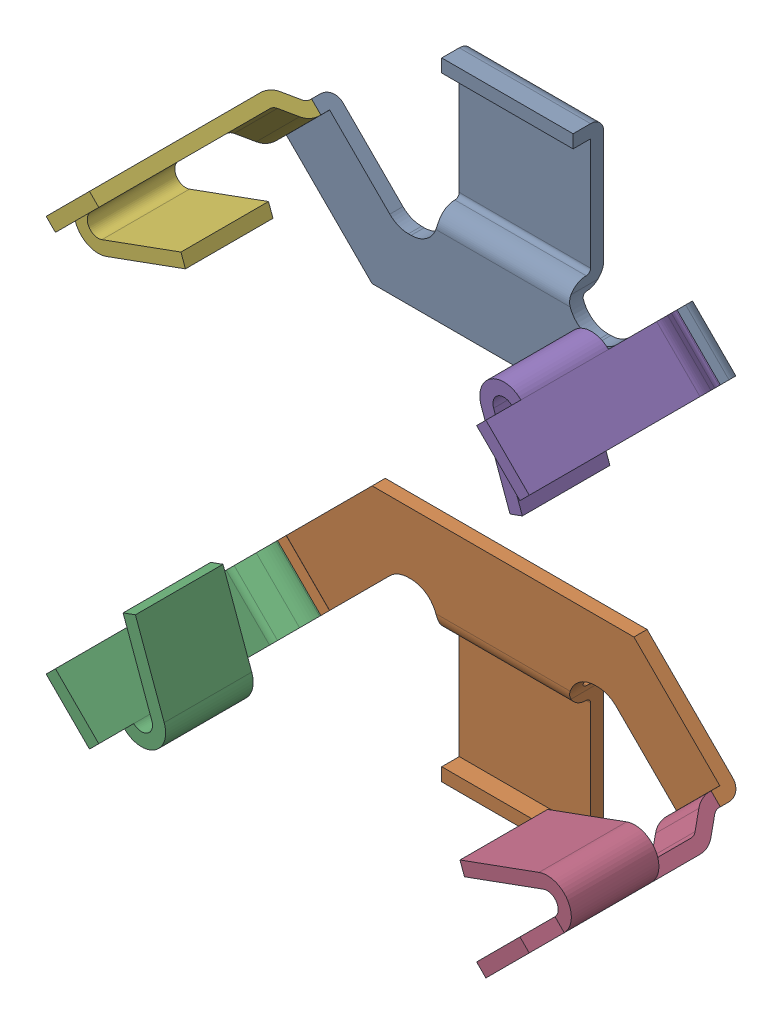
SolidWorks assembly Leadframe, configuration Default. Lengths in mm.
Overall size (7.19 7.19 3.21).
6 component instances, 3 part files, 0 mates.
Components (placement in the parent):
- Leadframe_3-1: Leadframe_3 [Default] at origin size (5.16 2.58 0.5)
- Leadframe_4-1: Leadframe_4 [Default] at origin size (5.16 2.58 0.5)
- contact-1: contact [Default] at (-2.3342 -2.3342 -3.3) x (0.5 -0.5 0.707107) z (0.707107 0.707107 0) size (2.16 2.16 0.93)
- contact-2: contact [Default] at (2.3342 -2.3342 -3.3) x (0.5 0.5 0.707107) z (-0.707107 0.707107 0) size (2.16 2.16 0.93)
- contact-3: contact [Default] at (2.3342 2.3342 -3.3) x (-0.5 0.5 0.707107) z (-0.707107 -0.707107 0) size (2.16 2.16 0.93)
- contact-4: contact [Default] at (-2.3342 2.3342 -3.3) x (-0.5 -0.5 0.707107) z (0.707107 -0.707107 0) size (2.16 2.16 0.93)
